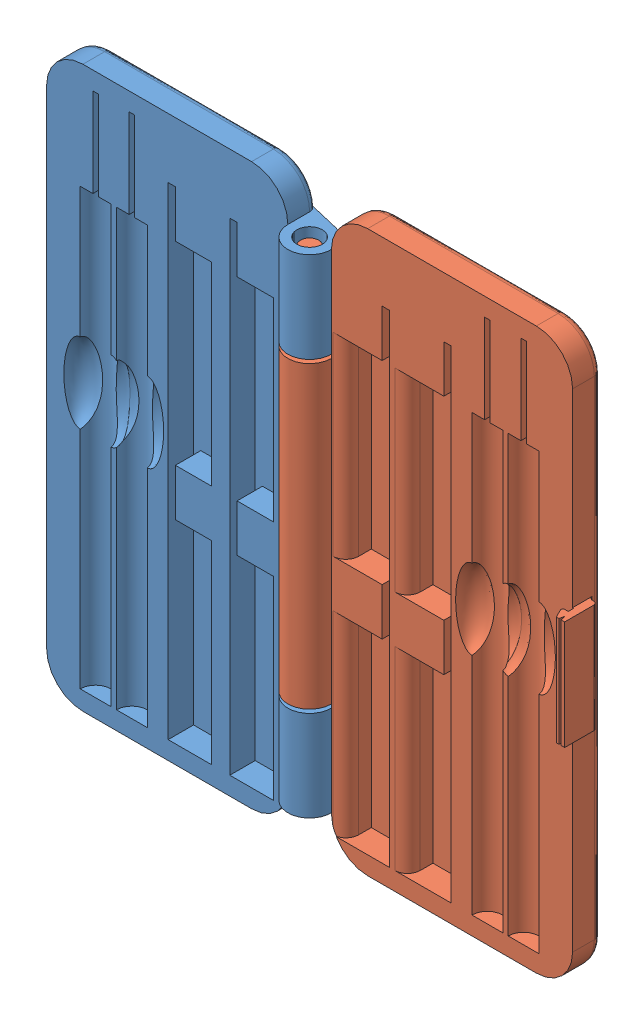
SolidWorks assembly Assembly, configuration Default. Lengths in mm.
Overall size (147.3 154.5 14).
2 component instances, 2 part files, 3 mates.
Components (placement in the parent):
- Case-1: Case [Default] at (-126.3994 46.3577 187.9366) x (-1 0 0) z (0 0 -1) size (78.5 154.5 14)
- MirrorCase-3: MirrorCase [Default] at (-8.3994 46.3577 187.9366) size (80.8 154.5 14)
Mates (geometry in assembly coordinates):
- Concentric1: concentric anti-aligned: cylinder of Case-1 through (-67.3994 76.3577 187.9366) axis (0 -1 0) radius 3.5; cylinder of MirrorCase-3 through (-67.3994 53.3577 187.9366) axis (0 1 0) radius 2.5
- Coincident1: coincident aligned: plane of Case-1 through (-73.3994 41.3577 187.9366) normal (0 -1 0); plane of MirrorCase-3 through (-61.3994 41.3577 187.9366) normal (0 -1 0)
- Coincident2: coincident aligned: plane of Case-1 through (-126.3994 166.3577 179.9366) normal (0 0 -1); plane of MirrorCase-3 through (-8.3994 166.3577 179.9366) normal (0 0 -1)
